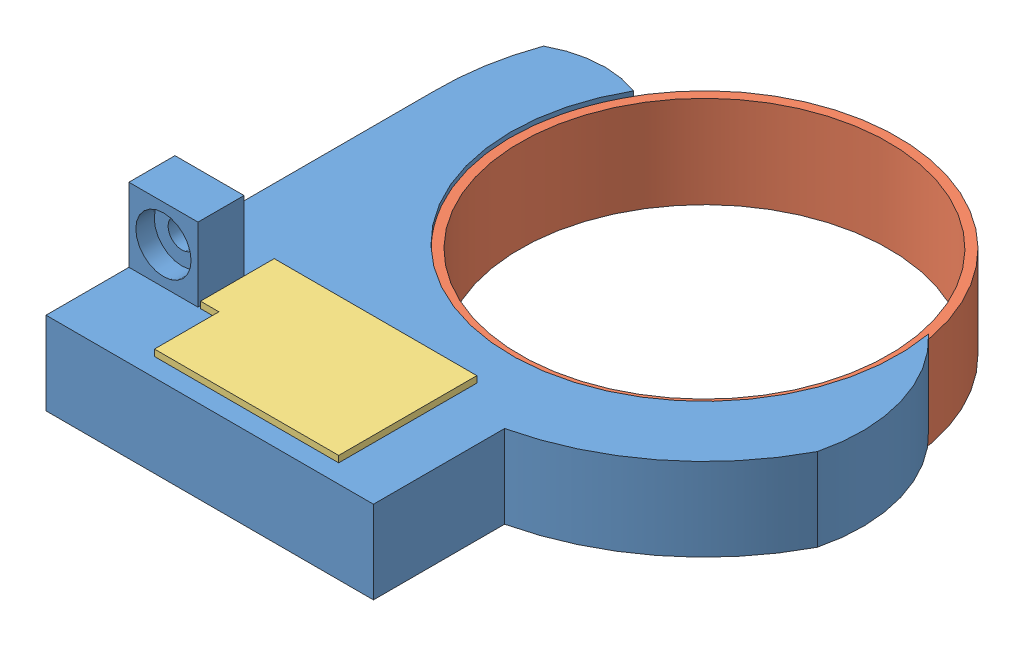
SolidWorks assembly fan assembly, configuration Default. Lengths in mm.
Overall size (55.23 18.5 66.74).
3 component instances, 3 part files, 4 mates.
Components (placement in the parent):
- Fan-1: Fan [Default] at (-43.9549 -8.8657 18.0284) size (55.23 17 53.67)
- fan exhaust lid-1: fan exhaust lid [Default] at (-43.9549 -10.3623 18.0284) x (0.985552 0 -0.169374) z (0.169374 0 0.985552) size (42 10 42)
- fanlid1-1: fanlid1 [Default] at (-53.1767 -0.1634 51.0131) x (-1 0 0) z (0 1 0) size (22 15 1)
Mates (geometry in assembly coordinates):
- Coincident1: coincident: plane of Fan-1 through (-43.9549 0.1343 18.0284) normal (0 1 0); plane of fanlid1-1 through (-43.9549 0.1343 42.0284) normal (0 1 0)
- Coincident2: coincident anti-aligned: plane of Fan-1 through (-43.1767 -1.3657 43.5131) normal (-1 0 0); plane of fanlid1-1 through (-43.1767 0.8366 43.5131) normal (1 0 0)
- Coincident3: coincident anti-aligned: plane of Fan-1 through (-63.1767 -1.3657 43.5131) normal (0 0 1); plane of fanlid1-1 through (-63.1767 0.8366 43.5131) normal (0 0 -1)
- Concentric1: concentric aligned: cylinder of Fan-1 through (-43.9549 0.1343 18.0284) axis (0 -1 0) radius 21; cylinder of fan exhaust lid-1 through (-43.9549 -0.3623 18.0284) axis (0 -1 0) radius 21
